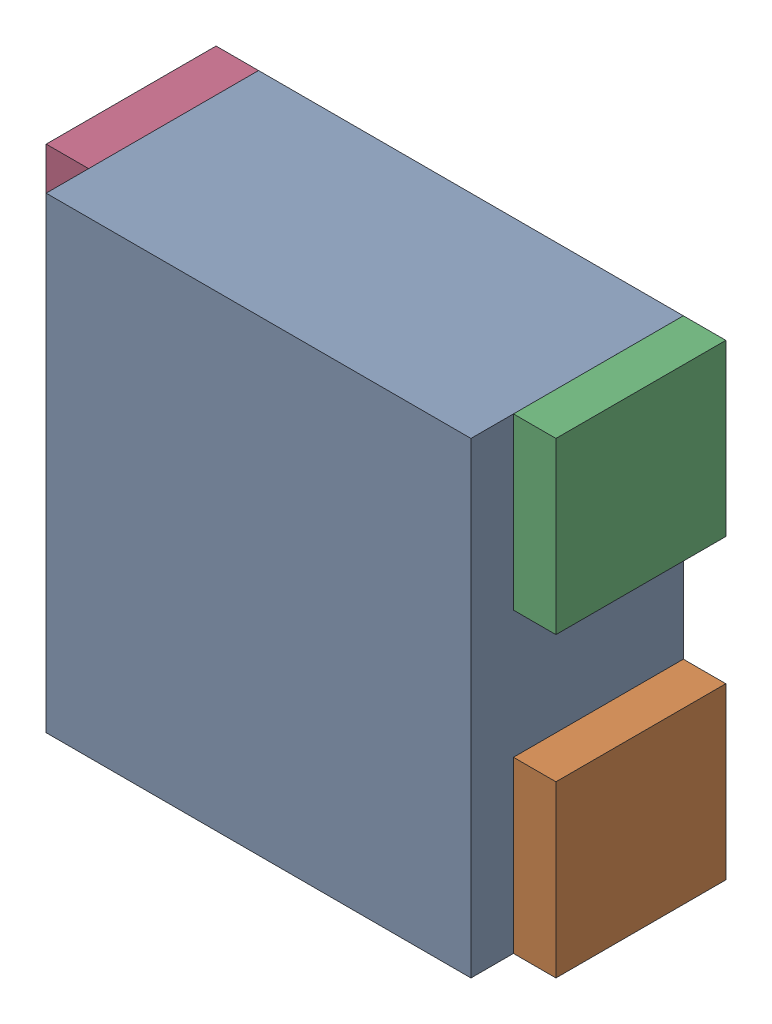
SolidWorks assembly RN2, configuration Default. Lengths in mm.
Overall size (1.2 1.1 0.5).
10 component instances, 2 part files, 0 mates.
Components (placement in the parent):
- 836749552-1: 836749552 [Default] at (132.65 17.35 0) size (1 1.1 0.5)
  - Extruded_11-1: Extruded_11 [Default] at origin size (1 1.1 0.5)
- 791587232-1: 791587232 [Default] at (133.2 17 0) size (0.1 0.4 0.4)
  - Extruded_10-1: Extruded_10 [Default] at origin size (0.1 0.4 0.4)
- 791587232-2: 791587232 [Default] at (133.2 17.7 0) size (0.1 0.4 0.4)
  - Extruded_10-1: Extruded_10 [Default] at origin size (0.1 0.4 0.4)
- 791587232-3: 791587232 [Default] at (132.1 17.7 0) size (0.1 0.4 0.4)
  - Extruded_10-1: Extruded_10 [Default] at origin size (0.1 0.4 0.4)
- 791587232-4: 791587232 [Default] at (132.1 17 0) size (0.1 0.4 0.4)
  - Extruded_10-1: Extruded_10 [Default] at origin size (0.1 0.4 0.4)
